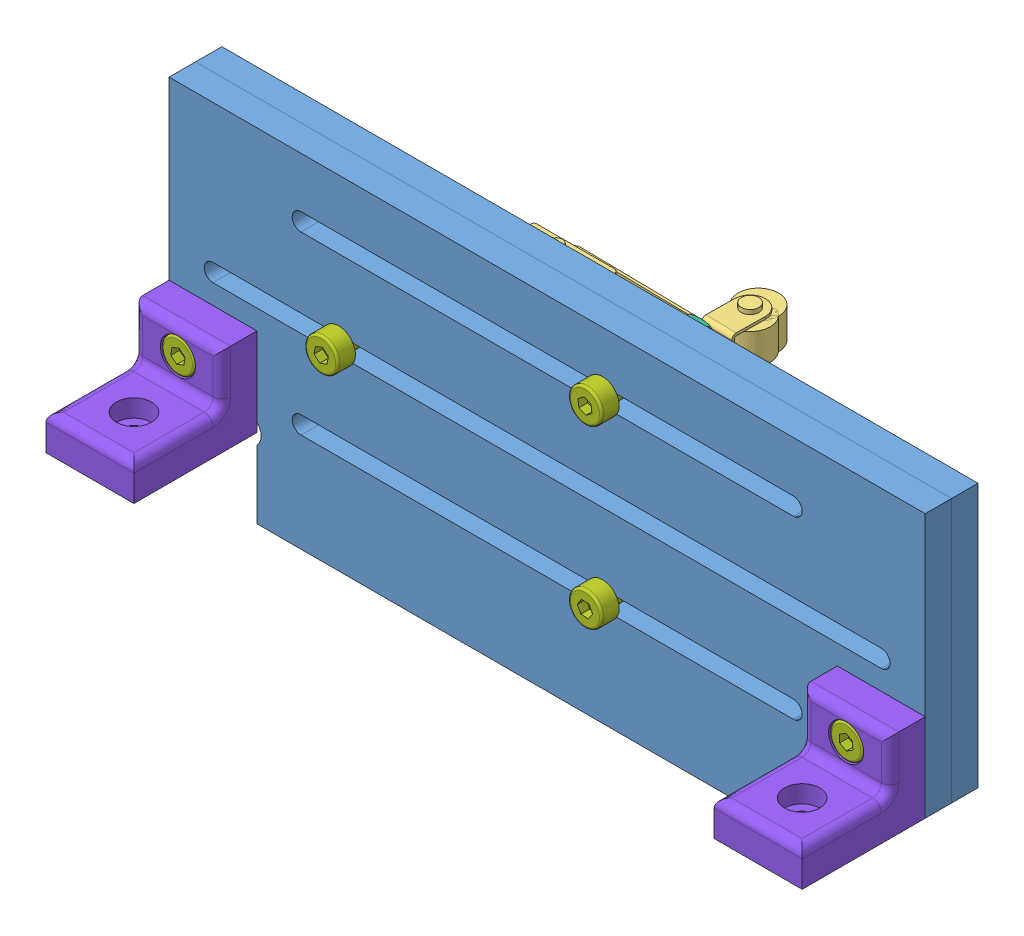
SolidWorks assembly cfc_ouvert, configuration Défaut. Lengths in mm.
Overall size (86 39 42.4).
21 component instances, 8 part files, 44 mates.
Components (placement in the parent):
- cfc-platine-1: cfc-platine [Défaut] at (140.8628 -70 0) x (0 0 1) z (0 -1 0) size (3 86 39)
- Grove microswitch v1.0-1: Grove microswitch v1.0 [Défaut] at (-48.6908 22.25 -3.344) x (-1 0 0) z (0 -1 0) size (41.8 22.4 23.6)
  - PCB grove 20x40-1: PCB grove 20x40 [Défaut] at (-1.988 -1.344 0) size (41.8 1.6 23.6)
  - microswitch 10T85-1: microswitch 10T85 [Défaut] at (9.562 0.256 0) size (22.48 22.4 6.4)
  - Connecteur Grove (coudé CMS)-1: Connecteur Grove (coudé CMS) [Défaut] at (-21.488 0.256 0) x (0 0 -1) z (0 1 0) size (12 10 5)
- entretoise-grove-1: entretoise-grove [Défaut] at (-66.7028 22.25 -2) x (1 0.000242 0) z (0 0 1) size (4 4 2)
- entretoise-grove-2: entretoise-grove [Défaut] at (-36.7028 32.25 -2) size (4 4 2)
- entretoise-grove-3: entretoise-grove [Défaut] at (-36.7028 12.25 -2) size (4 4 2)
- ecrou-h-2: ecrou-h [6007 HU M2] at (-36.7028 32.25 -5.2) x (-0.866025 0.5 0) z (-0.5 -0.866025 0) size (4 1.6 4.62)
- ecrou-h-3: ecrou-h [6007 HU M2] at (-36.7028 12.25 -5.2) x (0.866025 0.5 0) z (-0.5 0.866025 0) size (4 1.6 4.62)
- vis-chc-1: vis-chc [Vis CHC M2x12] at (-36.7028 32.25 6) x (0.144676 -0.989479 0) z (-0.989479 -0.144676 0) size (3.8 14 3.8)
- vis-chc-2: vis-chc [Vis CHC M2x12] at (-36.7028 12.25 6) x (0.999846 -0.017534 0) z (-0.017534 -0.999846 0) size (3.8 14 3.8)
- vis-chc-3: vis-chc [Vis CHC M2x12] at (-66.7028 22.25 6) x (-0.77641 0.630228 0) z (0.630228 0.77641 0) size (3.8 14 3.8)
- vis-chc-5: vis-chc [Vis CHC M2x10] at (-5 16 8) x (0.048861 -0.998806 0) z (-0.998806 -0.048861 0) size (3.8 12 3.8)
- vis-chc-6: vis-chc [Vis CHC M2x10] at (-81 16 8) x (-0.923728 -0.383049 0) z (-0.383049 0.923728 0) size (3.8 12 3.8)
- ecrou-h-6: ecrou-h [6007 HU M2] at (-81 16 -1.6) x (1 0 0) z (0 1 0) size (4 1.6 4.62)
- ecrou-h-8: ecrou-h [6007 HU M2] at (-5 16 -1.6) x (1 0 0) z (0 1 0) size (4 1.6 4.62)
- cfc-platine-2: cfc-platine [Défaut] at (140.8628 -70 3) x (0 0 1) z (0 -1 0) size (3 86 39)
- ecrou-h-4: ecrou-h [6007 HU M2] at (-66.7028 22.25 -5.2) x (1 0 0) z (0 1 0) size (4 1.6 4.62)
- equerre-basse-1: equerre-basse [Défaut] at (-81 9 6) size (10 10 14)
- equerre-basse-2: equerre-basse [Défaut] at (-5 9 6) size (10 10 14)
Mates (geometry in assembly coordinates):
- Coaxiale1: concentric anti-aligned: cylinder of Grove microswitch v1.0-1/PCB grove 20x40-1 through (-36.7028 12.25 -3.6) axis (0 0 1) radius 1.1; cylinder of entretoise-grove-3 through (-36.7028 12.25 0) axis (0 0 -1) radius 1
- Coïncidente4: coincident anti-aligned: plane of Grove microswitch v1.0-1/PCB grove 20x40-1 through (-46.7028 22.25 -2) normal (0 0 1); plane of entretoise-grove-3 through (-36.7028 12.25 -2) normal (0 0 -1)
- Coaxiale2: concentric anti-aligned: cylinder of Grove microswitch v1.0-1/PCB grove 20x40-1 through (-66.7028 22.25 -3.6) axis (0 0 1) radius 1.1; cylinder of entretoise-grove-1 through (-66.7028 22.25 0) axis (0 0 -1) radius 1
- Coïncidente5: coincident anti-aligned: plane of Grove microswitch v1.0-1/PCB grove 20x40-1 through (-46.7028 22.25 -2) normal (0 0 1); plane of entretoise-grove-1 through (-66.7028 22.25 -2) normal (0 0 -1)
- Coaxiale3: concentric anti-aligned: cylinder of Grove microswitch v1.0-1/PCB grove 20x40-1 through (-36.7028 32.25 -3.6) axis (0 0 1) radius 1.1; cylinder of entretoise-grove-2 through (-36.7028 32.25 0) axis (0 0 -1) radius 1
- Coïncidente6: coincident anti-aligned: plane of Grove microswitch v1.0-1/PCB grove 20x40-1 through (-46.7028 22.25 -2) normal (0 0 1); plane of entretoise-grove-2 through (-36.7028 32.25 -2) normal (0 0 -1)
- Coïncidente7: coincident anti-aligned: plane of cfc-platine-1 through (-8.8686 8.8686 0) normal (0 0 -1); plane of entretoise-grove-1 through (-66.7028 22.25 0) normal (0 0 1)
- Parallèle4: parallel aligned: plane of cfc-platine-1 through (-86 39 3) normal (-1 0 0); plane of Grove microswitch v1.0-1/PCB grove 20x40-1 through (-66.7028 22.25 -3.6) normal (-1 0 0)
- Parallèle3: parallel aligned: plane of cfc-platine-1 through (-10 0 3) normal (0 -1 0); plane of Grove microswitch v1.0-1/PCB grove 20x40-1 through (-46.7028 12.25 -3.6) normal (0 -1 0)
- Coaxiale4: concentric aligned: cylinder of Grove microswitch v1.0-1/PCB grove 20x40-1 through (-36.7028 32.25 -3.6) axis (0 0 1) radius 1.1; cylinder of vis-chc-1 through (-36.7028 32.25 -6) axis (0 0 1) radius 1
- Coaxiale5: concentric aligned: cylinder of Grove microswitch v1.0-1/PCB grove 20x40-1 through (-66.7028 22.25 -3.6) axis (0 0 1) radius 1.1; cylinder of vis-chc-3 through (-66.7028 22.25 -6) axis (0 0 1) radius 1
- Coaxiale6: concentric aligned: cylinder of Grove microswitch v1.0-1/PCB grove 20x40-1 through (-36.7028 12.25 -3.6) axis (0 0 1) radius 1.1; cylinder of vis-chc-2 through (-36.7028 12.25 -6) axis (0 0 1) radius 1
- Coaxiale7: concentric anti-aligned: cylinder of ecrou-h-2 through (-36.7028 32.25 -3.6) axis (0 0 -1) radius 0.7835; cylinder of vis-chc-1 through (-36.7028 32.25 -6) axis (0 0 1) radius 1
- Coaxiale8: concentric anti-aligned: cylinder of ecrou-h-3 through (-36.7028 12.25 -3.6) axis (0 0 -1) radius 0.7835; cylinder of vis-chc-2 through (-36.7028 12.25 -6) axis (0 0 1) radius 1
- Parallèle5: parallel aligned: plane of cfc-platine-1 through (0 39 3) normal (0 1 0); plane of ecrou-h-2 through (-37.8575 34.25 -3.6) normal (0 1 0)
- Parallèle7: parallel aligned: plane of ecrou-h-2 through (-37.8575 34.25 -3.6) normal (0 1 0); plane of ecrou-h-3 through (-37.8575 14.25 -3.6) normal (0 1 0)
- Tangent1: tangent anti-aligned: plane of cfc-platine-1 through (-15 31.25 3) normal (0 1 0); cylinder of vis-chc-1 through (-36.7028 32.25 -6) axis (0 0 1) radius 1
- Coïncidente17: coincident anti-aligned: plane of cfc-platine-1 through (-8.8686 8.8686 3) normal (0 0 1); plane of cfc-platine-2 through (-8.8686 8.8686 3) normal (0 0 -1)
- Coïncidente19: coincident aligned: plane of cfc-platine-1 through (-86 39 3) normal (-1 0 0); plane of cfc-platine-2 through (-86 39 6) normal (-1 0 0)
- Coïncidente20: coincident aligned: plane of cfc-platine-1 through (0 39 3) normal (0 1 0); plane of cfc-platine-2 through (0 39 6) normal (0 1 0)
- Coïncidente21: coincident anti-aligned: plane of vis-chc-3 through (-66.7028 22.25 6) normal (0 0 -1); plane of cfc-platine-2 through (-8.8686 8.8686 6) normal (0 0 1)
- Coaxiale9: concentric anti-aligned: cylinder of vis-chc-3 through (-66.7028 22.25 -6) axis (0 0 1) radius 1; cylinder of ecrou-h-4 through (-66.7028 22.25 -3.6) axis (0 0 -1) radius 0.7835
- Parallèle8: parallel aligned: plane of Grove microswitch v1.0-1/microswitch 10T85-1 through (-64.7028 19.25 -13.9) normal (-1 0 0); plane of ecrou-h-4 through (-68.7028 21.0953 -3.6) normal (-1 0 0)
- Coïncidente23: coincident anti-aligned: plane of Grove microswitch v1.0-1/PCB grove 20x40-1 through (-46.7028 22.25 -3.6) normal (0 0 -1); plane of ecrou-h-4 through (-64.7028 21.0953 -3.6) normal (0 0 1)
- Coïncidente24: coincident anti-aligned: plane of vis-chc-1 through (-36.7028 32.25 6) normal (0 0 -1); plane of cfc-platine-2 through (-8.8686 8.8686 6) normal (0 0 1)
- Coïncidente25: coincident anti-aligned: plane of Grove microswitch v1.0-1/PCB grove 20x40-1 through (-46.7028 22.25 -3.6) normal (0 0 -1); plane of ecrou-h-2 through (-37.8575 34.25 -3.6) normal (0 0 1)
- Parallèle9: parallel aligned: plane of Grove microswitch v1.0-1/PCB grove 20x40-1 through (-46.7028 32.25 -3.6) normal (0 1 0); plane of ecrou-h-2 through (-37.8575 34.25 -3.6) normal (0 1 0)
- Coïncidente28: coincident anti-aligned: plane of Grove microswitch v1.0-1/PCB grove 20x40-1 through (-46.7028 22.25 -3.6) normal (0 0 -1); plane of ecrou-h-3 through (-34.3934 12.25 -3.6) normal (0 0 1)
- Coïncidente29: coincident anti-aligned: plane of cfc-platine-2 through (-8.8686 8.8686 6) normal (0 0 1); plane of equerre-1 through (-81 9 6) normal (0 0 -1)
- Coïncidente30: coincident aligned: plane of cfc-platine-2 through (-86 39 6) normal (-1 0 0); plane of equerre-1 through (-86 19 10) normal (-1 0 0)
- Coïncidente31: coincident aligned: plane of cfc-platine-2 through (-78.726 9 6) normal (0 -1 0); plane of equerre-1 through (-86 9 10) normal (0 -1 0)
- Coaxiale10: concentric aligned: cylinder of equerre-1 through (-81 16 6) axis (0 0 1) radius 1; cylinder of vis-chc-6 through (-81 16 -2) axis (0 0 1) radius 1
- Coaxiale13: concentric anti-aligned: cylinder of cfc-platine-2 through (-5 16 6) axis (0 0 -1) radius 1; cylinder of vis-chc-5 through (-5 16 -2) axis (0 0 1) radius 1
- Coïncidente35: coincident anti-aligned: plane of equerre-1 through (-81 16 8) normal (0 0 1); plane of vis-chc-6 through (-81 16 8) normal (0 0 -1)
- Coïncidente36: coincident aligned: plane of equerre-1 through (-86 9 10) normal (0 -1 0); plane of equerre-2 through (-10 9 10) normal (0 -1 0)
- Coaxiale14: concentric anti-aligned: cylinder of cfc-platine-2 through (-5 16 6) axis (0 0 -1) radius 1; cylinder of equerre-2 through (-5 16 6) axis (0 0 1) radius 1
- Coaxiale17: concentric anti-aligned: cylinder of vis-chc-6 through (-81 16 -2) axis (0 0 1) radius 1; cylinder of ecrou-h-6 through (-81 16 0) axis (0 0 -1) radius 0.7835
- Coaxiale19: concentric anti-aligned: cylinder of vis-chc-5 through (-5 16 -2) axis (0 0 1) radius 1; cylinder of ecrou-h-8 through (-5 16 0) axis (0 0 -1) radius 0.7835
- Coïncidente38: coincident anti-aligned: plane of cfc-platine-1 through (-8.8686 8.8686 0) normal (0 0 -1); plane of ecrou-h-8 through (-3 14.8453 0) normal (0 0 1)
- Parallèle10: parallel aligned: plane of cfc-platine-1 through (0 9 3) normal (1 0 0); plane of ecrou-h-8 through (-3 17.1547 0) normal (1 0 0)
- Coïncidente44: coincident anti-aligned: plane of cfc-platine-1 through (-8.8686 8.8686 0) normal (0 0 -1); plane of ecrou-h-6 through (-79 14.8453 0) normal (0 0 1)
- Parallèle13: parallel aligned: plane of cfc-platine-1 through (-86 39 3) normal (-1 0 0); plane of ecrou-h-6 through (-83 14.8453 0) normal (-1 0 0)
- Coïncidente45: coincident anti-aligned: plane of cfc-platine-2 through (-8.8686 8.8686 6) normal (0 0 1); plane of equerre-2 through (-5 9 6) normal (0 0 -1)
- Coïncidente46: coincident anti-aligned: plane of vis-chc-5 through (-5 16 8) normal (0 0 -1); plane of equerre-2 through (-5 16 8) normal (0 0 1)
